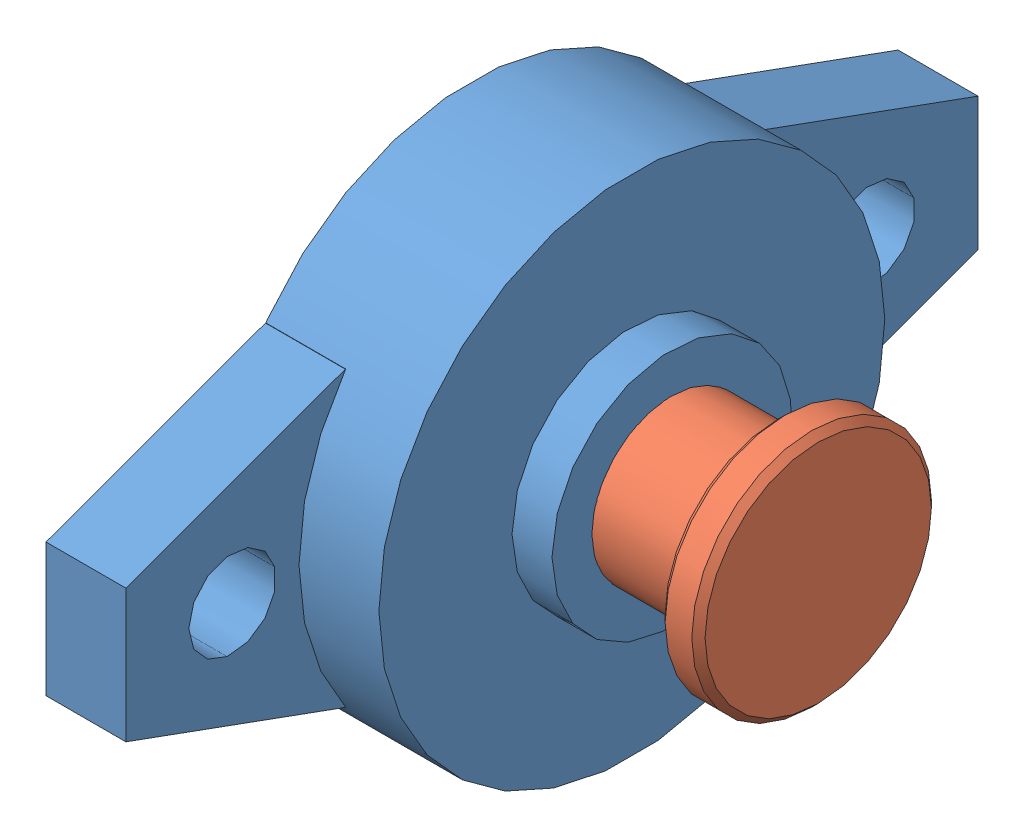
SolidWorks assembly wg_assembly, configuration Default. Lengths in mm.
Overall size (33 38 64).
2 component instances, 2 part files, 0 mates.
Components (placement in the parent):
- bearing_h-1: bearing_h [Default] at origin size (15 38 64)
- roll_fixator-1: roll_fixator [Default] at (23 0 0) x (0 0 -1) z (1 0 0) size (18 18 33)
